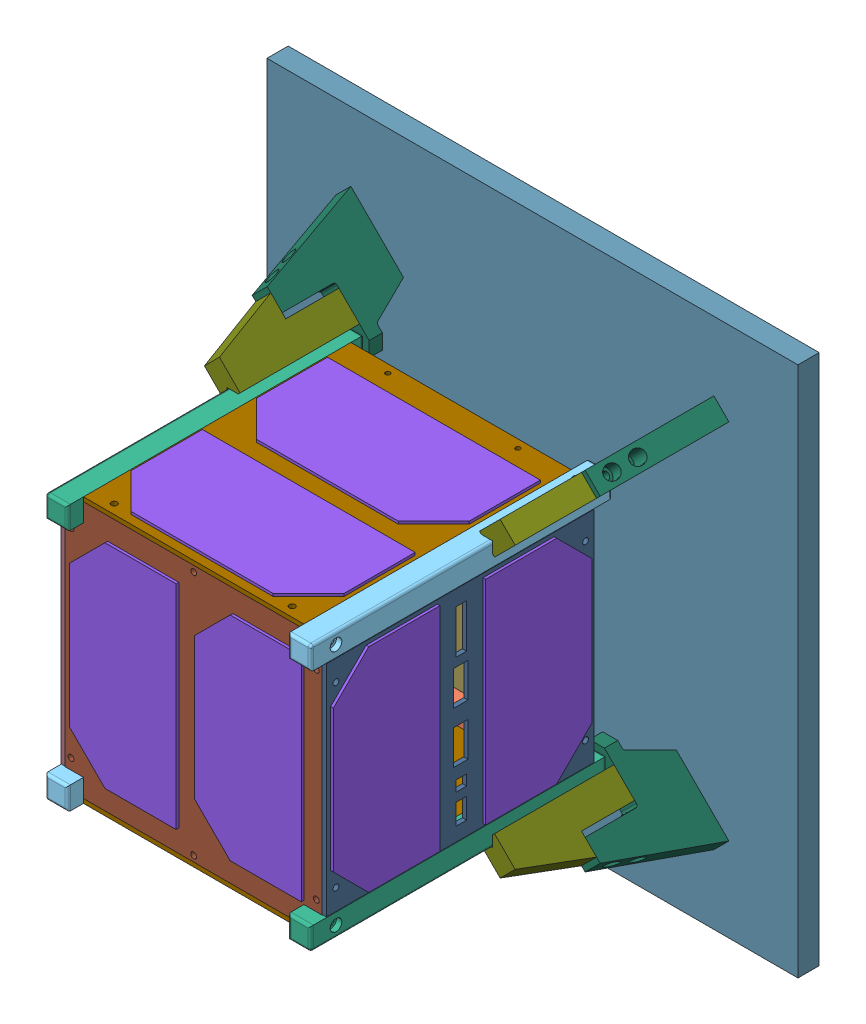
SolidWorks assembly stand_vertical, configuration ﾃﾞﾌｫﾙﾄ. Lengths in mm.
Overall size (200 200 141.5).
71 component instances, 17 part files, 76 mates.
Components (placement in the parent):
- sample-1: sample [ﾃﾞﾌｫﾙﾄ] at (-80.9327 45.2128 327.5) size (101 102 113.5)
  - B2_main-1: B2_main [ﾃﾞﾌｫﾙﾄ] at origin size (100 100 113.5)
    - B3_flame1-1: B3_flame1 [Default] at origin size (96.8 96.8 4)
    - B3_flame2-1: B3_flame2 [Default] at (76.5 -8.5 -87.5) x (-1 0 0) z (0 1 0) size (83 5 6.9)
    - B3_flame3-1: B3_flame3 [Default] at (100 -8.5 -85.4016) x (-1 0 0) z (0 1 0) size (6.9 5 83)
    - B3_flame4-1: B3_flame4 [Default] at (20.0069 -89.5 -26.6402) x (1 0 0) z (0 -1 0) size (6.9 16 10.5)
    - B3_flame5-1: B3_flame5 [Default] at (100 -8.5 11.5) x (-1 0 0) z (0 1 0) size (23.5 113.5 18.5)
    - B3_flame6-1: B3_flame6 [Default] at (91.5 -91.5 11.5) x (1 0 0) z (0 -1 0) size (23.5 111.5 18.5)
    - B3_flame5-2: B3_flame5 [Default] at (0 -91.5 11.5) x (1 0 0) z (0 -1 0) size (23.5 113.5 18.5)
    - B3_flame6-2: B3_flame6 [Default] at (8.5 -8.5 11.5) x (-1 0 0) z (0 1 0) size (23.5 111.5 18.5)
    - B3_flame2-2: B3_flame2 [Default] at (23.5 -91.5 -87.5) x (1 0 0) z (0 -1 0) size (83 5 6.9)
    - B3_flame3-2: B3_flame3 [Default] at (0 -91.5 -85.4016) x (1 0 0) z (0 -1 0) size (6.9 5 83)
    - B3_flame4-2: B3_flame4 [Default] at (79.9931 -10.5 -26.6402) x (-1 0 0) z (0 1 0) size (6.9 16 10.5)
    - B3_flame4-3: B3_flame4 [Default] at (-9.9069 -10.5 -26.6402) x (-1 0 0) z (0 1 0) size (6.9 16 10.5)
    - B3_flame4-4: B3_flame4 [Default] at (109.9069 -10.5 -61.3598) x (1 0 0) z (0 1 0) size (6.9 16 10.5)
    - B3_flame4-5: B3_flame4 [Default] at (109.9069 -89.5 -26.6402) x (1 0 0) z (0 -1 0) size (6.9 16 10.5)
    - B3_flame4-6: B3_flame4 [Default] at (-9.9069 -89.5 -61.3598) x (-1 0 0) z (0 -1 0) size (6.9 16 10.5)
    - B3_flame4-7: B3_flame4 [Default] at (79.9931 -89.5 -61.3598) x (-1 0 0) z (0 -1 0) size (6.9 16 10.5)
    - B3_flame4-8: B3_flame4 [Default] at (20.0069 -10.5 -61.3598) x (1 0 0) z (0 1 0) size (6.9 16 10.5)
    - B3_flame7-1: B3_flame7 [Default] at (4.25 -91.5 -96.25) x (1 0 0) z (0 -1 0) size (5.5 8.5 5)
    - B3_flame7-2: B3_flame7 [Default] at (95.75 -8.5 -96.25) x (-1 0 0) z (0 1 0) size (5.5 8.5 5)
  - B3_±Y_panel-1: B3_±Y_panel [Default] at (-6.4374 35.5175 36.7952) x (-1 0 0) z (0 0 -1) size (83 2.6 100.7)
    - Solar panel-1: Solar panel [Default] at (-43.4703 -35.5175 64.7205) size (80.15 1 40.15)
    - Solar panel-2: Solar panel [Default] at (-69.4046 -34.5175 111.8705) x (-1 0 0) z (0 0 1) size (80.15 1 40.15)
    - B2_±X_panel-2: B2_±X_panel [Default] at (-32.6974 -37.1175 99.3327) x (-1 0 0) z (0 0 -1) size (83 1.6 100.7)
  - B3_±Y_panel-2: B3_±Y_panel [Default] at (106.4374 -135.5175 36.7952) x (1 0 0) z (0 0 -1) size (83 2.6 100.7)
    - Solar panel-1: Solar panel [Default] at (-43.4703 -35.5175 64.7205) size (80.15 1 40.15)
    - Solar panel-2: Solar panel [Default] at (-69.4046 -34.5175 111.8705) x (-1 0 0) z (0 0 1) size (80.15 1 40.15)
    - B2_±X_panel-2: B2_±X_panel [Default] at (-32.6974 -37.1175 99.3327) x (-1 0 0) z (0 0 -1) size (83 1.6 100.7)
  - B3_+X_panel-1: B3_+X_panel [Default] at (78.7507 -74.7061 -48) x (0 1 0) z (0 0 -1) size (82.6 2.6 100.7)
    - Solar panel-2: Solar panel [Default] at (37.4682 21.2493 -21.6831) size (80.15 1 40.15)
    - Solar panel-3: Solar panel [Default] at (11.5339 21.2493 15.1831) x (-1 0 0) z (0 0 -1) size (80.15 1 40.15)
    - B3_+X_panel-1: B3_+X_panel [Default] at (0.9661 19.6493 -22.1375) size (82.6 1.6 100.7)
  - B3_+Z_panel-1: B3_+Z_panel [Default] at (-143.4944 -153.976 4.9) x (-1 0 0) z (0 1 0) size (96.8 2.6 96.8)
    - B2_+Z_panel-1: B2_+Z_panel [Default] at (-207.8501 -0.9 90.2045) size (96.8 1.6 96.8)
    - Solar panel-1: Solar panel [Default] at (-225.2113 0.7 116.9431) x (0 0 1) z (-1 0 0) size (80.15 1 40.15)
    - Solar panel-2: Solar panel [Default] at (-178.0613 1.7 91.0089) x (0 0 -1) z (-1 0 0) size (80.15 1 40.15)
  - B3_-Z_panel-1: B3_-Z_panel [ﾃﾞﾌｫﾙﾄ] at (67.2 -63 -89) x (1 0 0) z (0 -1 0) size (96.8 2.6 96.8)
    - B2_-Z_panel-1: B2_-Z_panel [Default] at (-49.4929 -4.5 -25.7556) x (0 0 1) z (1 0 0) size (96.8 1.6 96.8)
    - Solar panel-1: Solar panel [Default] at (15.6169 -6.1 -0.1079) x (0 0 1) z (1 0 0) size (80.15 1 40.15)
    - Solar panel-2: Solar panel [Default] at (-31.5331 -7.1 -26.0421) x (0 0 -1) z (1 0 0) size (80.15 1 40.15)
  - B3_-X_panel-1: B3_-X_panel [Default] at (0 -73.74 -25.8625) x (0 1 0) z (0 0 -1) size (82.6 1.6 100.7)
- base-1: base [ﾃﾞﾌｫﾙﾄ] at (-130.9327 -104.7872 197.5) size (200 200 8)
- holder-6: holder [ﾃﾞﾌｫﾙﾄ] at (43.0483 -73.1113 205.5) x (0 0 1) z (-0.707107 -0.707107 0) size (40 42 8)
- holder-7: holder [ﾃﾞﾌｫﾙﾄ] at (-104.9771 63.6004 205.5) x (0 0 1) z (0.707107 0.707107 0) size (40 42 8)
- holder-8: holder [ﾃﾞﾌｫﾙﾄ] at (-99.3203 -78.7682 205.5) x (0 0 1) z (-0.707107 0.707107 0) size (40 42 8)
- holder-5: holder [ﾃﾞﾌｫﾙﾄ] at (37.3915 69.2573 205.5) x (0 0 1) z (0.707107 -0.707107 0) size (40 42 8)
- suport-7: suport [ﾃﾞﾌｫﾙﾄ] at (27.5556 59.4214 245.5) x (0.707107 0.707107 0) z (0.707107 -0.707107 0) size (19 45 8)
- suport-8: suport [ﾃﾞﾌｫﾙﾄ] at (-89.4844 -68.9323 245.5) x (-0.707107 -0.707107 0) z (-0.707107 0.707107 0) size (19 45 8)
- suport-5: suport [ﾃﾞﾌｫﾙﾄ] at (33.2125 -63.2755 245.5) x (0.707107 -0.707107 0) z (-0.707107 -0.707107 0) size (19 45 8)
- suport-6: suport [ﾃﾞﾌｫﾙﾄ] at (-95.1413 53.7645 245.5) x (-0.707107 0.707107 0) z (0.707107 0.707107 0) size (19 45 8)
- SSHS-M2-10-1: SSHS-M2-10 [ﾃﾞﾌｫﾙﾄ] at (-92.2492 56.5293 239.5) x (0.707107 -0.707107 0) z (-0.617466 -0.617466 -0.487311) size (11.1 4 4) (hidden)
- SSHS-M2-10-2: SSHS-M2-10 [ﾃﾞﾌｫﾙﾄ] at (-92.2492 56.5293 231.5) x (0.707107 -0.707107 0) z (-0.704411 -0.704411 -0.087235) size (11.1 4 4) (hidden)
- SSHS-M2-10-9: SSHS-M2-10 [ﾃﾞﾌｫﾙﾄ] at (-92.2492 -66.0402 239.5) x (0.707107 0.707107 0) z (0.528103 -0.528103 0.664992) size (11.1 4 4) (hidden)
- SSHS-M2-10-10: SSHS-M2-10 [ﾃﾞﾌｫﾙﾄ] at (-92.2492 -66.0402 231.5) x (0.707107 0.707107 0) z (-0.698689 0.698689 0.153839) size (11.1 4 4) (hidden)
- SSHS-M2-10-11: SSHS-M2-10 [ﾃﾞﾌｫﾙﾄ] at (30.3204 -66.0402 231.5) x (-0.707107 0.707107 0) z (0.431911 0.431911 0.791774) size (11.1 4 4) (hidden)
- SSHS-M2-10-12: SSHS-M2-10 [ﾃﾞﾌｫﾙﾄ] at (30.3204 -66.0402 239.5) x (-0.707107 0.707107 0) z (0.523201 0.523201 0.672697) size (11.1 4 4) (hidden)
- SSHS-M2-10-13: SSHS-M2-10 [ﾃﾞﾌｫﾙﾄ] at (30.3204 56.5293 231.5) x (-0.707107 -0.707107 0) z (0.387956 -0.387956 -0.836051) size (11.1 4 4) (hidden)
- SSHS-M2-10-14: SSHS-M2-10 [ﾃﾞﾌｫﾙﾄ] at (30.3204 56.5293 239.5) x (-0.707107 -0.707107 0) z (0.690366 -0.690366 0.216307) size (11.1 4 4) (hidden)
- SSHS-M2-10-15: SSHS-M2-10 [ﾃﾞﾌｫﾙﾄ] at (34.563 -70.2829 201.5) x (0 0 1) z (-0.999656 -0.026213 0) size (11.1 4 4) (hidden)
- SSHS-M2-10-16: SSHS-M2-10 [ﾃﾞﾌｫﾙﾄ] at (23.2493 -58.9692 201.5) x (0 0 1) z (-0.997649 -0.068535 0) size (11.1 4 4) (hidden)
- SSHS-M2-10-17: SSHS-M2-10 [ﾃﾞﾌｫﾙﾄ] at (-96.4918 60.772 201.5) x (0 0 1) z (-0.997649 -0.068535 0) size (11.1 4 4) (hidden)
- SSHS-M2-10-18: SSHS-M2-10 [ﾃﾞﾌｫﾙﾄ] at (-96.4918 -70.2829 201.5) x (0 0 1) z (0.388711 -0.92136 0) size (11.1 4 4) (hidden)
- SSHS-M2-10-19: SSHS-M2-10 [ﾃﾞﾌｫﾙﾄ] at (28.9062 -64.626 201.5) x (0 0 1) z (-0.997649 -0.068535 0) size (11.1 4 4) (hidden)
- SSHS-M2-10-20: SSHS-M2-10 [ﾃﾞﾌｫﾙﾄ] at (-85.1781 -58.9692 201.5) x (0 0 1) z (-0.982544 0.186028 0) size (11.1 4 4) (hidden)
- SSHS-M2-10-21: SSHS-M2-10 [ﾃﾞﾌｫﾙﾄ] at (-90.835 -64.626 201.5) x (0 0 1) z (-0.997649 -0.068535 0) size (11.1 4 4) (hidden)
- SSHS-M2-10-22: SSHS-M2-10 [ﾃﾞﾌｫﾙﾄ] at (23.2493 49.4583 201.5) x (0 0 1) z (-0.997649 -0.068535 0) size (11.1 4 4) (hidden)
- SSHS-M2-10-23: SSHS-M2-10 [ﾃﾞﾌｫﾙﾄ] at (-85.1781 49.4583 201.5) x (0 0 1) z (-0.997649 -0.068535 0) size (11.1 4 4) (hidden)
- SSHS-M2-10-24: SSHS-M2-10 [ﾃﾞﾌｫﾙﾄ] at (-90.835 55.1151 201.5) x (0 0 1) z (-0.997649 -0.068535 0) size (11.1 4 4) (hidden)
- SSHS-M2-10-25: SSHS-M2-10 [ﾃﾞﾌｫﾙﾄ] at (28.9062 55.1151 201.5) x (0 0 1) z (-0.997649 -0.068535 0) size (11.1 4 4) (hidden)
- SSHS-M2-10-26: SSHS-M2-10 [ﾃﾞﾌｫﾙﾄ] at (34.563 60.772 201.5) x (0 0 1) z (-0.997649 -0.068535 0) size (11.1 4 4) (hidden)
Mates (geometry in assembly coordinates):
- Coincident29: coincident anti-aligned: plane of base-1 through (-130.9327 -104.7872 205.5) normal (0 0 1); plane of holder-8 through (-104.9771 -73.1113 205.5) normal (0 0 -1)
- Coincident31: coincident anti-aligned: plane of holder-8 through (-75.2786 -43.4128 225.5) normal (0 0 1); plane of suport-8 through (-89.4844 -57.6186 225.5) normal (0 0 -1)
- Coincident32: coincident aligned: plane of holder-8 through (-99.3203 -78.7682 205.5) normal (0.707107 -0.707107 0); plane of suport-8 through (-89.4844 -68.9323 245.5) normal (0.707107 -0.707107 0)
- Coincident34: coincident anti-aligned: plane of base-1 through (-130.9327 -104.7872 205.5) normal (0 0 1); plane of holder-7 through (-99.3203 69.2573 205.5) normal (0 0 -1)
- Coincident35: coincident anti-aligned: plane of holder-7 through (-69.6218 39.5588 225.5) normal (0 0 1); plane of suport-6 through (-83.8275 53.7645 225.5) normal (0 0 -1)
- Coincident37: coincident aligned: plane of holder-7 through (-104.9771 63.6004 205.5) normal (-0.707107 -0.707107 0); plane of suport-6 through (-95.1413 53.7645 245.5) normal (-0.707107 -0.707107 0)
- Coincident38: coincident anti-aligned: plane of base-1 through (-130.9327 -104.7872 205.5) normal (0 0 1); plane of holder-6 through (37.3915 -78.7682 205.5) normal (0 0 -1)
- Coincident40: coincident anti-aligned: plane of holder-6 through (7.693 -49.0697 225.5) normal (0 0 1); plane of suport-5 through (21.8987 -63.2755 225.5) normal (0 0 -1)
- Coincident41: coincident aligned: plane of holder-6 through (43.0483 -73.1113 205.5) normal (0.707107 0.707107 0); plane of suport-5 through (33.2125 -63.2755 245.5) normal (0.707107 0.707107 0)
- Coincident42: coincident anti-aligned: plane of holder-5 through (43.0483 63.6004 205.5) normal (0 0 -1); plane of base-1 through (-130.9327 -104.7872 205.5) normal (0 0 1)
- Coincident43: coincident anti-aligned: plane of holder-5 through (13.3498 33.9019 225.5) normal (0 0 1); plane of suport-7 through (27.5556 48.1077 225.5) normal (0 0 -1)
- Coincident45: coincident aligned: plane of holder-5 through (37.3915 69.2573 205.5) normal (-0.707107 0.707107 0); plane of suport-7 through (27.5556 59.4214 245.5) normal (-0.707107 0.707107 0)
- Parallel9: parallel aligned: plane of base-1 through (-130.9327 -104.7872 205.5) normal (-1 0 0); plane of suport-7 through (19.0703 45.2793 225.5) normal (-1 0 0)
- Parallel10: parallel aligned: plane of base-1 through (-130.9327 -104.7872 205.5) normal (-1 0 0); plane of suport-5 through (19.0703 -50.5475 225.5) normal (-1 0 0)
- Parallel11: parallel aligned: plane of base-1 through (69.0673 -104.7872 205.5) normal (1 0 0); plane of suport-6 through (-80.9991 41.0366 225.5) normal (1 0 0)
- Parallel12: parallel aligned: plane of base-1 through (69.0673 -104.7872 205.5) normal (1 0 0); plane of suport-8 through (-80.9991 -54.7902 225.5) normal (1 0 0)
- Coincident55: coincident anti-aligned: plane of holder-5 through (13.3498 33.9019 225.5) normal (0 0 1); plane of sample-1/B2_main-1/B3_flame5-1 through (19.0673 45.2128 225.5) normal (0 0 -1)
- Parallel13: parallel anti-aligned: plane of suport-6 through (-80.9991 45.2793 225.5) normal (0 -1 0); plane of sample-1/B2_main-1/B3_flame6-2 through (-72.4327 45.2128 339) normal (0 1 0)
- Concentric1: concentric anti-aligned: cylinder of holder-7 through (-92.2492 56.5293 231.5) axis (0.707107 -0.707107 0) radius 1.5; cylinder of SSHS-M2-10-2 through (-85.1781 49.4583 231.5) axis (-0.707107 0.707107 0) radius 0.8
- Concentric2: concentric anti-aligned: cylinder of holder-7 through (-92.2492 56.5293 239.5) axis (0.707107 -0.707107 0) radius 1.5; cylinder of SSHS-M2-10-1 through (-85.1781 49.4583 239.5) axis (-0.707107 0.707107 0) radius 0.8
- Concentric3: concentric anti-aligned: cylinder of holder-8 through (-102.1487 -75.9397 231.5) axis (0.707107 0.707107 0) radius 2.5; cylinder of SSHS-M2-10-10 through (-85.1781 -58.9692 231.5) axis (-0.707107 -0.707107 0) radius 0.8
- Concentric4: concentric anti-aligned: cylinder of holder-8 through (-92.2492 -66.0402 239.5) axis (0.707107 0.707107 0) radius 1.5; cylinder of SSHS-M2-10-9 through (-85.1781 -58.9692 239.5) axis (-0.707107 -0.707107 0) radius 0.8
- Concentric5: concentric anti-aligned: cylinder of holder-6 through (40.2199 -75.9397 231.5) axis (-0.707107 0.707107 0) radius 2.5; cylinder of SSHS-M2-10-11 through (23.2493 -58.9692 231.5) axis (0.707107 -0.707107 0) radius 0.8
- Concentric6: concentric anti-aligned: cylinder of holder-6 through (30.3204 -66.0402 239.5) axis (-0.707107 0.707107 0) radius 1.5; cylinder of SSHS-M2-10-12 through (23.2493 -58.9692 239.5) axis (0.707107 -0.707107 0) radius 0.8
- Concentric7: concentric anti-aligned: cylinder of holder-5 through (30.3204 56.5293 239.5) axis (-0.707107 -0.707107 0) radius 1.5; cylinder of SSHS-M2-10-14 through (23.2493 49.4583 239.5) axis (0.707107 0.707107 0) radius 0.8
- Concentric8: concentric anti-aligned: cylinder of holder-5 through (40.2199 66.4288 231.5) axis (-0.707107 -0.707107 0) radius 2.5; cylinder of SSHS-M2-10-13 through (23.2493 49.4583 231.5) axis (0.707107 0.707107 0) radius 0.8
- Coincident66: coincident aligned: plane of SSHS-M2-10-16 through (23.2493 -58.9692 200.4) normal (0 0 -1); plane of SSHS-M2-10-17 through (-96.4918 60.772 200.4) normal (0 0 -1)
- Coincident67: coincident aligned: plane of SSHS-M2-10-17 through (-96.4918 60.772 200.4) normal (0 0 -1); plane of SSHS-M2-10-18 through (-96.4918 -70.2829 200.4) normal (0 0 -1)
- Coincident68: coincident aligned: plane of SSHS-M2-10-18 through (-96.4918 -70.2829 200.4) normal (0 0 -1); plane of SSHS-M2-10-19 through (28.9062 -64.626 200.4) normal (0 0 -1)
- Coincident69: coincident aligned: plane of SSHS-M2-10-19 through (28.9062 -64.626 200.4) normal (0 0 -1); plane of SSHS-M2-10-20 through (-85.1781 -58.9692 200.4) normal (0 0 -1)
- Coincident70: coincident aligned: plane of SSHS-M2-10-20 through (-85.1781 -58.9692 200.4) normal (0 0 -1); plane of SSHS-M2-10-21 through (-90.835 -64.626 200.4) normal (0 0 -1)
- Coincident71: coincident aligned: plane of SSHS-M2-10-21 through (-90.835 -64.626 200.4) normal (0 0 -1); plane of SSHS-M2-10-22 through (23.2493 49.4583 200.4) normal (0 0 -1)
- Coincident72: coincident aligned: plane of SSHS-M2-10-22 through (23.2493 49.4583 200.4) normal (0 0 -1); plane of SSHS-M2-10-23 through (-85.1781 49.4583 200.4) normal (0 0 -1)
- Coincident73: coincident aligned: plane of SSHS-M2-10-23 through (-85.1781 49.4583 200.4) normal (0 0 -1); plane of SSHS-M2-10-24 through (-90.835 55.1151 200.4) normal (0 0 -1)
- Coincident74: coincident aligned: plane of SSHS-M2-10-24 through (-90.835 55.1151 200.4) normal (0 0 -1); plane of SSHS-M2-10-25 through (28.9062 55.1151 200.4) normal (0 0 -1)
- Coincident75: coincident aligned: plane of SSHS-M2-10-25 through (28.9062 55.1151 200.4) normal (0 0 -1); plane of SSHS-M2-10-26 through (34.563 60.772 200.4) normal (0 0 -1)
- Distance6: distance = 50 mm aligned: plane of sample-1/B2_main-1/B3_flame5-2 through (-80.9327 -54.7872 339) normal (0 -1 0); plane of base-1 through (-130.9327 -104.7872 205.5) normal (0 -1 0)
- Distance7: distance = 50 mm aligned: plane of sample-1/B2_main-1/B3_flame6-1 through (19.0673 -54.7872 339) normal (1 0 0); plane of base-1 through (69.0673 -104.7872 205.5) normal (1 0 0)
- Concentric9: concentric anti-aligned: cylinder of base-1 through (-85.1781 -58.9692 201.5) axis (0 0 1) radius 1.5; cylinder of SSHS-M2-10-20 through (-85.1781 -58.9692 211.5) axis (0 0 -1) radius 2
- Concentric10: concentric anti-aligned: cylinder of base-1 through (-90.835 -64.626 201.5) axis (0 0 1) radius 1.5; cylinder of SSHS-M2-10-21 through (-90.835 -64.626 211.5) axis (0 0 -1) radius 2
- Concentric11: concentric anti-aligned: cylinder of base-1 through (-96.4918 -70.2829 201.5) axis (0 0 1) radius 1.5; cylinder of SSHS-M2-10-18 through (-96.4918 -70.2829 211.5) axis (0 0 -1) radius 2
- Concentric12: concentric anti-aligned: cylinder of base-1 through (-85.1781 49.4583 201.5) axis (0 0 1) radius 1.5; cylinder of SSHS-M2-10-23 through (-85.1781 49.4583 211.5) axis (0 0 -1) radius 0.8
- Concentric13: concentric anti-aligned: cylinder of base-1 through (-90.835 55.1151 201.5) axis (0 0 1) radius 1.5; cylinder of SSHS-M2-10-24 through (-90.835 55.1151 211.5) axis (0 0 -1) radius 0.8
- Concentric14: concentric anti-aligned: cylinder of base-1 through (-96.4918 60.772 201.5) axis (0 0 1) radius 1.5; cylinder of SSHS-M2-10-17 through (-96.4918 60.772 211.5) axis (0 0 -1) radius 0.8
- Concentric15: concentric anti-aligned: cylinder of base-1 through (23.2493 49.4583 191.5) axis (0 0 1) radius 2.5; cylinder of SSHS-M2-10-22 through (23.2493 49.4583 211.5) axis (0 0 -1) radius 0.8
- Concentric16: concentric anti-aligned: cylinder of base-1 through (28.9062 55.1151 191.5) axis (0 0 1) radius 2.5; cylinder of SSHS-M2-10-25 through (28.9062 55.1151 211.5) axis (0 0 -1) radius 0.8
- Concentric17: concentric anti-aligned: cylinder of base-1 through (34.563 60.772 191.5) axis (0 0 1) radius 2.5; cylinder of SSHS-M2-10-26 through (34.563 60.772 211.5) axis (0 0 -1) radius 0.8
- Concentric18: concentric anti-aligned: cylinder of base-1 through (34.563 -70.2829 191.5) axis (0 0 1) radius 2.5; cylinder of SSHS-M2-10-15 through (34.563 -70.2829 211.5) axis (0 0 -1) radius 2
- Concentric19: concentric anti-aligned: cylinder of base-1 through (28.9062 -64.626 191.5) axis (0 0 1) radius 2.5; cylinder of SSHS-M2-10-19 through (28.9062 -64.626 211.5) axis (0 0 -1) radius 0.8
- Concentric20: concentric anti-aligned: cylinder of base-1 through (23.2493 -58.9692 191.5) axis (0 0 1) radius 2.5; cylinder of SSHS-M2-10-16 through (23.2493 -58.9692 211.5) axis (0 0 -1) radius 0.8
- Coincident84: coincident aligned: plane of SSHS-M2-10-15 through (34.563 -70.2829 200.4) normal (0 0 -1); plane of SSHS-M2-10-19 through (28.9062 -64.626 200.4) normal (0 0 -1)
- Coincident85: coincident aligned: plane of base-1 through (34.563 -70.2829 201.5) normal (0 0 -1); circle of SSHS-M2-10-15
- Concentric21: concentric anti-aligned: cylinder of base-1 through (23.2493 -58.9692 201.5) axis (0 0 1) radius 1.5; cylinder of holder-6 through (23.2493 -58.9692 205.5) axis (0 0 -1) radius 0.8
- Concentric22: concentric anti-aligned: cylinder of base-1 through (23.2493 49.4583 201.5) axis (0 0 1) radius 1.5; circle of holder-5
- Concentric23: concentric anti-aligned: cylinder of base-1 through (-85.1781 49.4583 201.5) axis (0 0 1) radius 1.5; cylinder of holder-7 through (-85.1781 49.4583 205.5) axis (0 0 -1) radius 0.8
- Concentric24: concentric anti-aligned: cylinder of base-1 through (-85.1781 -58.9692 201.5) axis (0 0 1) radius 1.5; cylinder of holder-8 through (-85.1781 -58.9692 205.5) axis (0 0 -1) radius 0.8
- LimitDistance1: limit distance = 1.91 mm anti-aligned: plane of holder-5 through (28.9062 49.4583 225.5) normal (-0.707107 -0.707107 0); plane of suport-7 through (27.5556 48.1077 245.5) normal (0.707107 0.707107 0)
- LimitDistance2: limit distance = 1.91 mm anti-aligned: plane of suport-5 through (21.8987 -63.2755 245.5) normal (0.707107 -0.707107 0); plane of holder-6 through (23.2493 -64.626 225.5) normal (-0.707107 0.707107 0)
- LimitDistance3: limit distance = 1.91 mm anti-aligned: plane of suport-8 through (-89.4844 -57.6186 245.5) normal (-0.707107 -0.707107 0); plane of holder-8 through (-90.835 -58.9692 225.5) normal (0.707107 0.707107 0)
- LimitDistance4: limit distance = 1.91 mm anti-aligned: plane of suport-6 through (-83.8275 53.7645 245.5) normal (-0.707107 0.707107 0); plane of holder-7 through (-85.1781 55.1151 225.5) normal (0.707107 -0.707107 0)
- Screw1: screw = 0.4 aligned: cylinder of suport-8 through (-86.656 -60.447 239.5) axis (-0.707107 -0.707107 0) radius 0.8; cylinder of SSHS-M2-10-9 through (-85.1781 -58.9692 239.5) axis (-0.707107 -0.707107 0) radius 0.8
- Screw2: screw = 0.4 aligned: cylinder of suport-8 through (-86.656 -60.447 231.5) axis (-0.707107 -0.707107 0) radius 0.8; cylinder of SSHS-M2-10-10 through (-85.1781 -58.9692 231.5) axis (-0.707107 -0.707107 0) radius 0.8
- Coincident88: coincident aligned: plane of SSHS-M2-10-9 through (-93.027 -66.8181 239.5) normal (-0.707107 -0.707107 0); plane of SSHS-M2-10-10 through (-93.027 -66.8181 231.5) normal (-0.707107 -0.707107 0)
- Coincident89: coincident aligned: plane of SSHS-M2-10-11 through (31.0982 -66.8181 231.5) normal (0.707107 -0.707107 0); plane of SSHS-M2-10-12 through (31.0982 -66.8181 239.5) normal (0.707107 -0.707107 0)
- Coincident90: coincident aligned: plane of SSHS-M2-10-13 through (31.0982 57.3071 231.5) normal (0.707107 0.707107 0); circle of SSHS-M2-10-14
- Coincident91: coincident aligned: plane of SSHS-M2-10-1 through (-93.027 57.3071 239.5) normal (-0.707107 0.707107 0); plane of SSHS-M2-10-2 through (-93.027 57.3071 231.5) normal (-0.707107 0.707107 0)
- Coincident92: coincident anti-aligned: plane of holder-8 through (-92.2492 -66.0402 239.5) normal (-0.707107 -0.707107 0); plane of SSHS-M2-10-9 through (-93.1896 -65.0998 240.9937) normal (0.707107 0.707107 0)
- Screw3: screw = 0.4 aligned: cylinder of suport-6 through (-86.656 50.9361 239.5) axis (-0.707107 0.707107 0) radius 0.8; cylinder of SSHS-M2-10-1 through (-85.1781 49.4583 239.5) axis (-0.707107 0.707107 0) radius 0.8
- Screw4: screw = 0.4 aligned: cylinder of suport-6 through (-86.656 50.9361 231.5) axis (-0.707107 0.707107 0) radius 0.8; cylinder of SSHS-M2-10-2 through (-85.1781 49.4583 231.5) axis (-0.707107 0.707107 0) radius 0.8
- Coincident93: coincident anti-aligned: plane of holder-7 through (-92.2492 56.5293 239.5) normal (-0.707107 0.707107 0); plane of SSHS-M2-10-1 through (-92.9384 55.8402 241.2465) normal (0.707107 -0.707107 0)
- Screw5: screw = 0.4 aligned: cylinder of suport-7 through (24.7272 50.9361 239.5) axis (0.707107 0.707107 0) radius 0.8; cylinder of SSHS-M2-10-14 through (23.2493 49.4583 239.5) axis (0.707107 0.707107 0) radius 0.8
- Screw6: screw = 0.4 aligned: cylinder of suport-7 through (24.7272 50.9361 231.5) axis (0.707107 0.707107 0) radius 0.8; cylinder of SSHS-M2-10-13 through (23.2493 49.4583 231.5) axis (0.707107 0.707107 0) radius 0.8
- Coincident94: coincident anti-aligned: plane of holder-5 through (30.3204 56.5293 239.5) normal (0.707107 0.707107 0); plane of SSHS-M2-10-14 through (30.6263 56.2234 237.5473) normal (-0.707107 -0.707107 0)
- Screw7: screw = 0.4 aligned: cylinder of suport-5 through (24.7272 -60.447 239.5) axis (0.707107 -0.707107 0) radius 0.8; cylinder of SSHS-M2-10-12 through (23.2493 -58.9692 239.5) axis (0.707107 -0.707107 0) radius 0.8
- Screw8: screw = 0.4 aligned: cylinder of suport-5 through (24.7272 -60.447 231.5) axis (0.707107 -0.707107 0) radius 0.8; cylinder of SSHS-M2-10-11 through (23.2493 -58.9692 231.5) axis (0.707107 -0.707107 0) radius 0.8
- Coincident95: coincident anti-aligned: plane of holder-6 through (30.3204 -66.0402 239.5) normal (0.707107 -0.707107 0); plane of SSHS-M2-10-12 through (29.369 -66.9916 240.9798) normal (-0.707107 0.707107 0)
